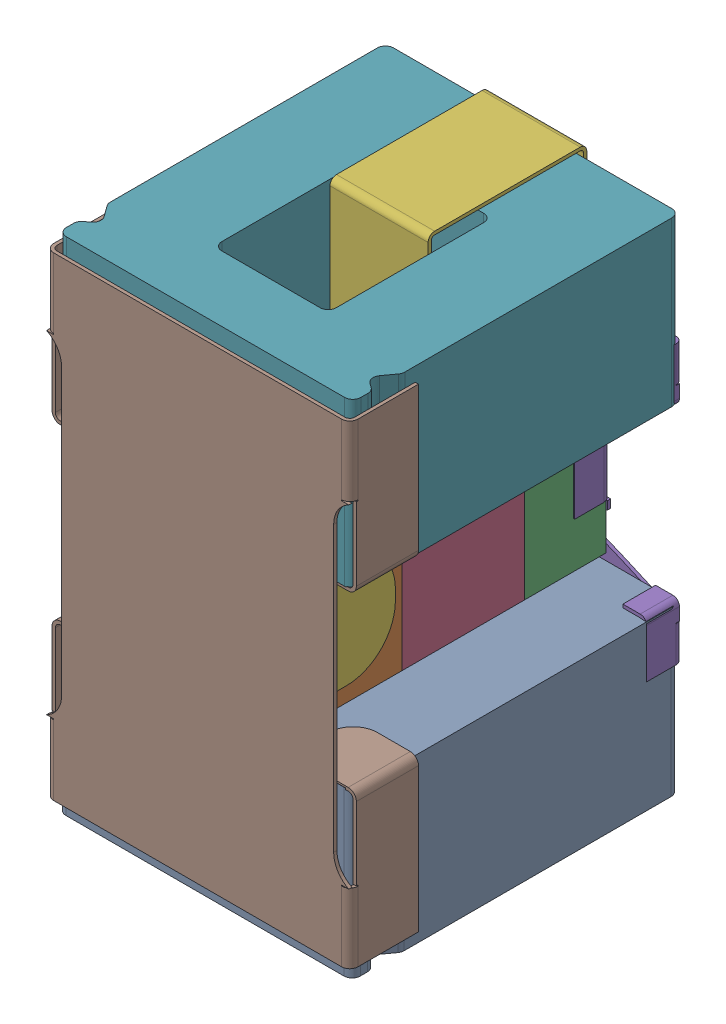
SolidWorks assembly U300_1PCB, configuration Default. Lengths in mm.
Overall size (1.86 3.21 2.06).
7 component instances, 5 part files, 0 mates.
Components (placement in the parent):
- User_Library-filterassy-1-1: User_Library-filterassy-1 [Default] at (160.5061 111.3876 0.0128) x (0 1 0) z (1 0 0) size (3.21 2.06 1.86)
  - User_Library-filterassy-1_ferrite001_1-1: User_Library-filterassy-1_ferrite001_1 [Default] at (-1.7182 1.0098 -0.0449) x (0 0 -1) z (1 0 0) size (1.8 2 1)
  - User_Library-filterassy-1_0603cap_1-1: User_Library-filterassy-1_0603cap_1 [Default] at (-0.2006 0.895 0.4524) x (0 -1 0) z (1 0 0) size (1.75 0.9 0.95)
  - User_Library-filterassy-1_bottom_bracketSLDPRT_1-1: User_Library-filterassy-1_bottom_bracketSLDPRT_1 [Default] at origin size (1.7 0.22 1.8)
  - User_Library-filterassy-1_cap_top_hat_1-1: User_Library-filterassy-1_cap_top_hat_1 [Default] at (-0.1923 1.79 0.0135) x (-1 0 0) z (0 0 1) size (3.21 1.79 1)
  - User_Library-filterassy-1_ferrite001_1-2: User_Library-filterassy-1_ferrite001_1 [Default] at (0.3475 1.0098 -0.0411) x (0 0 -1) z (1 0 0) size (1.8 2 1)
  - User_Library-filterassy-1_top_1-1: User_Library-filterassy-1_top_1 [Default] at (-0.1875 2.0589 -0.0063) x (-1 0 0) z (0 0 1) size (2.9 0.42 1.86)
